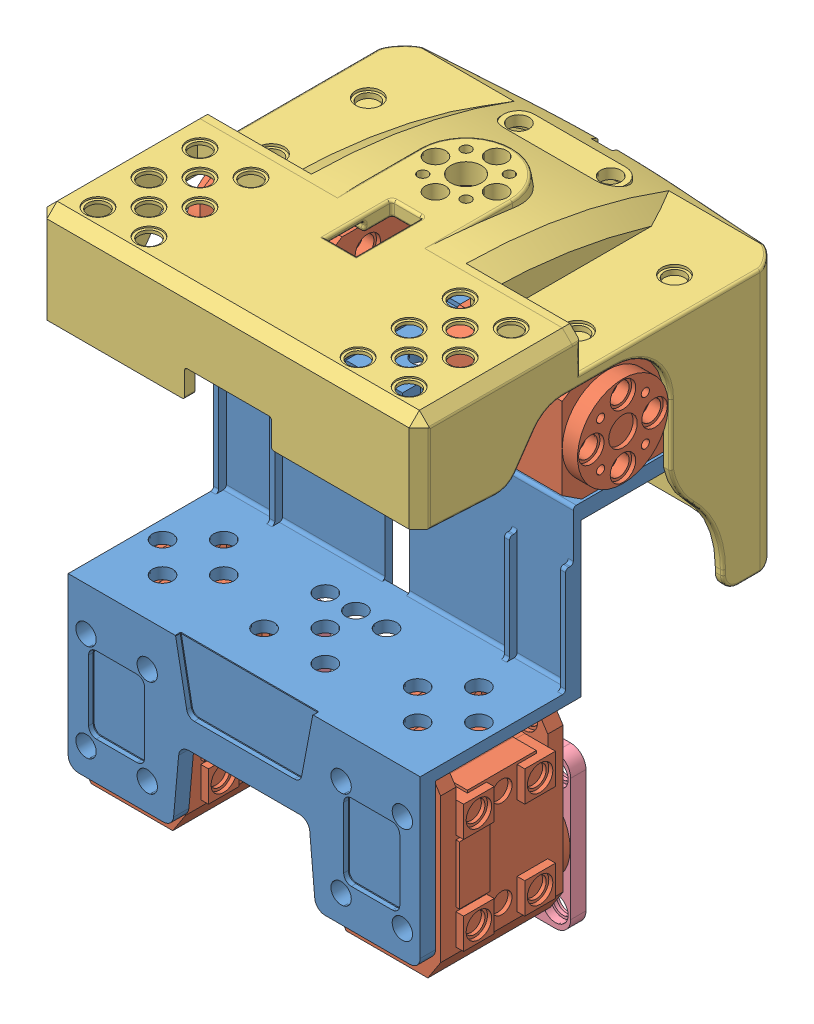
SolidWorks assembly bodyAsm, configuration Default. Lengths in mm.
Overall size (77.13 106.3 74.8).
8 component instances, 4 part files, 32 mates.
Components (placement in the parent):
- frm_body-1: frm_body [Default] at origin size (69 84.64 63.04)
- XL-1: XL [Default] at (23.5 13.5 -2.0876) x (0 -1 0) z (1 0 0) size (24 36 27)
- XL-2: XL [Default] at (-23.5 13.5 -2.0876) x (0 1 0) z (-1 0 0) size (24 36 27)
- XL-3: XL [Default] at (-25 -47.7 27.75) x (-1 0 0) z (0 0 -1) size (24 36 27)
- XL-4: XL [Default] at (25 -47.7 27.75) x (-1 0 0) z (0 0 -1) size (24 36 27)
- body-1: body [Default] at (0.5 34.5 16.4124) x (-1 0 0) z (0 0 -1) size (76.25 60.08 74.8)
- cvt-2: cvt [Default] at (-25 -56.8 12.75) x (0 1 0) z (-1 0 0) size (30 3 18)
- cvt-3: cvt [Default] at (25 -56.8 12.75) x (0 -1 0) z (1 0 0) size (30 3 18)
Mates (geometry in assembly coordinates):
- Coincident1: coincident aligned: plane of frm_body-1 through (0 0 0) normal (0 0 1)
- Coincident2: coincident aligned: plane of frm_body-1 through (0 0 0) normal (0 1 0)
- Coincident3: coincident aligned: plane of frm_body-1 through (0 0 0) normal (1 0 0)
- Coincident4: coordinate: point of frm_body-1
- Parallel2: parallel anti-aligned: plane of frm_body-1 through (0 0 0) normal (0 1 0); plane of XL-1 through (23.5 13.5 -2.0876) normal (0 -1 0)
- Concentric1: concentric aligned: cylinder of frm_body-1 through (29.5 2.3 7.9124) axis (0 -1 0) radius 2.5; cylinder of XL-1 through (29.5 2.3 7.9124) axis (0 -1 0) radius 2.5
- Coincident8: coincident anti-aligned: plane of frm_body-1 through (29.5 2.3 7.9124) normal (0 1 0); plane of XL-1 through (29.5 2.3 7.9124) normal (0 -1 0)
- Concentric2: concentric aligned: cylinder of frm_body-1 through (29.5 2.3 -11.0876) axis (0 -1 0) radius 2.5; cylinder of XL-1 through (29.5 2.3 -11.0876) axis (0 -1 0) radius 2.5
- Parallel3: parallel aligned: plane of frm_body-1 through (0 0 0) normal (0 1 0); plane of XL-2 through (-23.5 13.5 -2.0876) normal (0 1 0)
- Concentric3: concentric aligned: cylinder of frm_body-1 through (-29.5 2.3 7.9124) axis (0 -1 0) radius 2.5; cylinder of XL-2 through (-29.5 2.3 7.9124) axis (0 -1 0) radius 2.5
- Concentric4: concentric aligned: cylinder of frm_body-1 through (-29.5 2.3 -11.0876) axis (0 -1 0) radius 2.5; cylinder of XL-2 through (-29.5 2.3 -11.0876) axis (0 -1 0) radius 2.5
- Coincident10: coincident anti-aligned: plane of frm_body-1 through (-29.5 2.3 -11.0876) normal (0 1 0); plane of XL-2 through (-29.5 2.3 -11.0876) normal (0 -1 0)
- Parallel4: parallel anti-aligned: plane of frm_body-1 through (0 0 0) normal (0 0 1); plane of XL-3 through (-25 -47.7 27.75) normal (0 0 -1)
- Concentric5: concentric aligned: cylinder of frm_body-1 through (-31 -56.8 38.95) axis (0 0 1) radius 2.5; cylinder of XL-3 through (-31 -56.8 38.95) axis (0 0 1) radius 2.5
- Coincident12: coincident anti-aligned: circle of frm_body-1; plane of XL-3 through (-31 -56.8 38.95) normal (0 0 1)
- Parallel5: parallel aligned: plane of frm_body-1 through (0 0 0) normal (0 1 0); plane of XL-3 through (-25 -47.7 27.75) normal (0 1 0)
- Concentric6: concentric aligned: cylinder of frm_body-1 through (19 -56.8 38.95) axis (0 0 1) radius 2.5; cylinder of XL-4 through (19 -56.8 38.95) axis (0 0 1) radius 2.5
- Parallel6: parallel anti-aligned: plane of frm_body-1 through (0 0 0) normal (0 0 1); plane of XL-4 through (25 -47.7 27.75) normal (0 0 -1)
- Parallel7: parallel anti-aligned: plane of frm_body-1 through (0 0 0) normal (1 0 0); plane of XL-4 through (25 -47.7 27.75) normal (-1 0 0)
- Coincident17: coincident anti-aligned: plane of frm_body-1 through (19 -56.8 38.95) normal (0 0 -1); plane of XL-4 through (19 -56.8 38.95) normal (0 0 1)
- Parallel11: parallel anti-aligned: plane of frm_body-1 through (0 0 0) normal (0 0 1); plane of body-1 through (0.5 34.5 16.4124) normal (0 0 -1)
- Parallel12: parallel aligned: plane of frm_body-1 through (0 0 0) normal (0 1 0); plane of body-1 through (0.5 34.5 16.4124) normal (0 1 0)
- Concentric8: concentric aligned: cylinder of XL-2 through (-29.5 24.7 -11.0876) axis (0 1 0) radius 2.5; cylinder of body-1 through (-29.5 24.7 -11.0876) axis (0 1 0) radius 2.5
- Coincident22: coincident anti-aligned: plane of XL-2 through (-35.5 24 -16.2376) normal (0 1 0); plane of body-1 through (-29.5 24 -11.0876) normal (0 -1 0)
- Parallel13: parallel aligned: plane of XL-3 through (-25 -47.7 27.75) normal (0 0 -1); plane of cvt-2 through (-25 -56.8 12.75) normal (0 0 -1)
- Concentric12: concentric anti-aligned: circle of XL-3; circle of cvt-2
- Coincident28: coincident anti-aligned: plane of XL-3 through (-25 -56.8 12.75) normal (0 0 -1); plane of cvt-2 through (-31 -44.8 12.75) normal (0 0 1)
- Parallel17: parallel aligned: plane of XL-3 through (-25 -47.7 27.75) normal (0 1 0); plane of cvt-2 through (-25 -56.8 12.75) normal (0 1 0)
- Parallel18: parallel aligned: plane of XL-4 through (25 -47.7 27.75) normal (0 0 -1); plane of cvt-3 through (25 -56.8 12.75) normal (0 0 -1)
- Parallel19: parallel anti-aligned: plane of XL-4 through (25 -47.7 27.75) normal (0 1 0); plane of cvt-3 through (25 -56.8 12.75) normal (0 -1 0)
- Concentric13: concentric anti-aligned: circle of XL-4; circle of cvt-3
- Coincident32: coincident anti-aligned: plane of XL-4 through (25 -56.8 12.75) normal (0 0 -1); plane of cvt-3 through (31 -68.8 12.75) normal (0 0 1)
